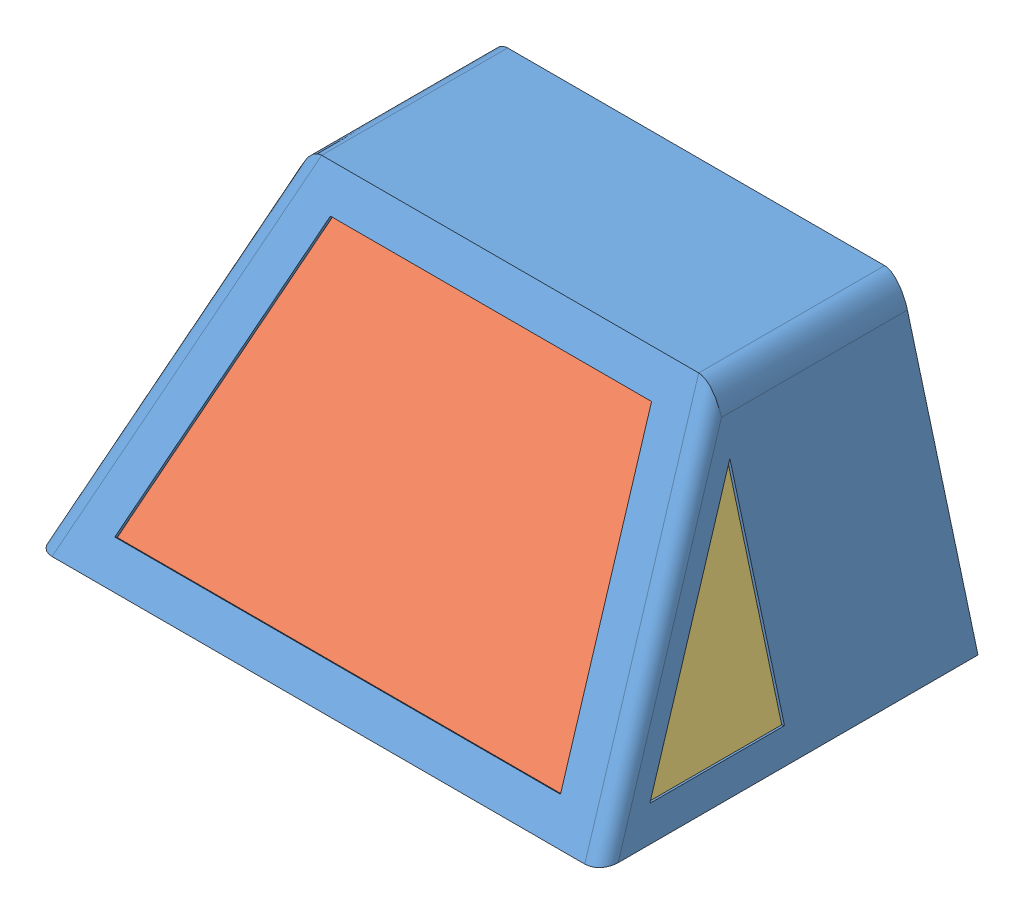
SolidWorks assembly front shell, configuration Default. Lengths in mm.
Overall size (615.95 317.5 412.75).
4 component instances, 3 part files, 0 mates.
Components (placement in the parent):
- front shell-1-1: front shell-1 [Default] at origin size (615.95 317.5 412.75)
- front window-1-1: front window-1 [Default] at (0 24.7142 187.5324) x (1 0 0) z (0 0.550842 0.834609) size (488.95 311.15 1.59)
- side window-1-1: side window-1 [Default] at (-296.6907 29.8464 -12.7) x (0 0 -1) z (0.965926 -0.258819 0) size (165.1 254.23 1.59)
- side window-1-2: side window-1 [Default] at (295.1573 29.4355 -12.7) x (0 0 -1) z (0.965926 0.258819 0) size (165.1 254.23 1.59)
